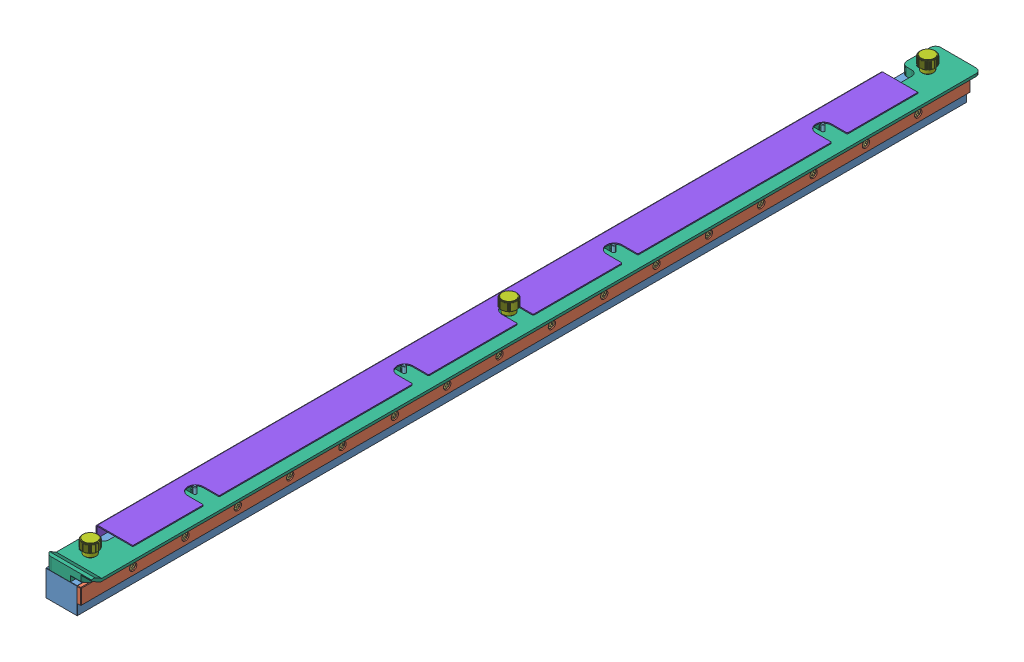
SolidWorks assembly Assemblage, configuration Défaut. Lengths in mm.
Overall size (95 92 1700).
40 component instances, 10 part files, 81 mates.
Components (placement in the parent):
- platine laterale-1: platine laterale [Défaut] at (-34.0319 -22.1151 2250) size (60 50 1700)
- teflon lateral-1: teflon lateral [Défaut] at (25.9681 -2.1151 2250) x (0 0 -1) z (1 0 0) size (1700 30 7)
- vis-1: vis [Défaut] at (31.6181 12.8849 2150) x (-1 0 0) z (0 -0.924225 -0.381849) size (12.65 11.3 11.3)
- vis-2: vis [Défaut] at (31.6181 12.8849 1950) x (-1 0 0) z (0 -0.924225 -0.381849) size (12.65 11.3 11.3)
- vis-3: vis [Défaut] at (31.6181 12.8849 2050) x (-1 0 0) z (0 -0.924225 -0.381849) size (12.65 11.3 11.3)
- vis-4: vis [Défaut] at (31.6181 12.8849 1850) x (-1 0 0) z (0 -0.924225 -0.381849) size (12.65 11.3 11.3)
- vis-5: vis [Défaut] at (31.6181 12.8849 1750) x (-1 0 0) z (0 -0.178078 0.984016) size (12.65 11.3 11.3)
- vis-6: vis [Défaut] at (31.6181 12.8849 1650) x (-1 0 0) z (0 0.474768 -0.880111) size (12.65 11.3 11.3)
- vis-8: vis [Défaut] at (31.6181 12.8849 1550) x (-1 0 0) z (0 -0.634119 -0.773236) size (12.65 11.3 11.3)
- vis-9: vis [Défaut] at (31.6181 12.8849 1450) x (-1 0 0) z (0 -0.237453 0.971399) size (12.65 11.3 11.3)
- vis-10: vis [Défaut] at (31.6181 12.8849 1350) x (-1 0 0) z (0 -0.971622 0.236541) size (12.65 11.3 11.3)
- vis-11: vis [Défaut] at (31.6181 12.8849 1250) x (-1 0 0) z (0 -0.306125 -0.951991) size (12.65 11.3 11.3)
- vis-12: vis [Défaut] at (31.6181 12.8849 1150) x (-1 0 0) z (0 -0.680899 0.732377) size (12.65 11.3 11.3)
- vis-13: vis [Défaut] at (31.6181 12.8849 1050) x (-1 0 0) z (0 -0.480013 0.877262) size (12.65 11.3 11.3)
- vis-14: vis [Défaut] at (31.6181 12.8849 950) x (-1 0 0) z (0 -0.325442 -0.945562) size (12.65 11.3 11.3)
- vis-15: vis [Défaut] at (31.6181 12.8849 850) x (-1 0 0) z (0 -0.999367 -0.035574) size (12.65 11.3 11.3)
- vis-16: vis [Défaut] at (31.6181 12.8849 750) x (-1 0 0) z (0 -0.091177 0.995835) size (12.65 11.3 11.3)
- vis-17: vis [Défaut] at (31.6181 12.8849 650) x (-1 0 0) z (0 -0.904322 0.426851) size (12.65 11.3 11.3)
- tige filetee-6: tige filetee [Défaut] at (0.9681 6.8849 2200) x (-0.474745 0 0.880123) z (0 1 0) size (8.23 8 60.82)
- tige filetee-7: tige filetee [Défaut] at (0.9681 6.8849 600) x (-0.873701 0 0.486463) z (0 1 0) size (8.23 8 60.82)
- pige-1: pige [Défaut] at (0.9681 5.8849 2000) x (-0.994545 0 0.104312) z (0 1 0) size (6 6 50)
- pige-2: pige [Défaut] at (0.9681 5.8849 1200) x (0.060452 0 -0.998171) z (0 1 0) size (6 6 50)
- pige-3: pige [Défaut] at (0.9681 5.8849 800) x (0.10136 0 0.99485) z (0 1 0) size (6 6 50)
- pige-4: pige [Défaut] at (0.9681 5.8849 1600) x (-0.928161 0 -0.37218) z (0 1 0) size (6 6 50)
- ski-1: ski [Défaut] at (-34.0319 27.8849 2250) size (87 23.5 1700)
- bouton molete-1: bouton molete [Défaut] at (0.9681 43.8849 600) x (0.383728 0 0.923446) z (-0.923446 0 0.383728) size (30 26 29.98)
- bouton molete-2: bouton molete [Défaut] at (0.9681 43.8849 2200) x (0.858497 0 0.512818) z (-0.512818 0 0.858497) size (30 26 29.98)
- equerre-1: equerre [Défaut] at (-37.6319 -17.1151 650) x (0 0 1) z (-1 0 0) size (1500 65 70)
- rondelle plate-1: rondelle plate [Défaut] at (-34.0319 2.8849 670) x (0 0 1) z (-1 0 0) size (16 16 1.6)
- rondelle plate-2: rondelle plate [Défaut] at (-34.0319 2.8849 1035) x (0 0 1) z (-1 0 0) size (16 16 1.6)
- rondelle plate-3: rondelle plate [Défaut] at (-34.0319 2.8849 2130) x (0 0 1) z (-1 0 0) size (16 16 1.6)
- rondelle plate-4: rondelle plate [Défaut] at (-34.0319 2.8849 1765) x (0 0 1) z (-1 0 0) size (16 16 1.6)
- rondelle plate-5: rondelle plate [Défaut] at (-34.0319 2.8849 1400) x (0 0 1) z (-1 0 0) size (16 16 1.6)
- vis bombe m8-6: vis bombe m8 [Défaut] at (-42.0319 2.8849 670) size (19.4 17.8 17.8)
- vis bombe m8-7: vis bombe m8 [Défaut] at (-42.0319 2.8849 1035) size (19.4 17.8 17.8)
- vis bombe m8-8: vis bombe m8 [Défaut] at (-42.0319 2.8849 1400) size (19.4 17.8 17.8)
- vis bombe m8-9: vis bombe m8 [Défaut] at (-42.0319 2.8849 1765) size (19.4 17.8 17.8)
- vis bombe m8-10: vis bombe m8 [Défaut] at (-42.0319 2.8849 2130) size (19.4 17.8 17.8)
- tige filetee-8: tige filetee [Défaut] at (0.9681 6.8849 1400) x (0.48993 0 -0.871762) z (0 1 0) size (8.23 8 60.82)
- bouton molete-3: bouton molete [Défaut] at (0.9681 43.8849 1400) x (0.825158 0 0.564902) z (-0.564902 0 0.825158) size (30 26 29.98)
Mates (geometry in assembly coordinates):
- Coaxiale1: concentric aligned: cylinder of teflon lateral-1 through (32.9681 12.8849 2150) axis (-1 0 0) radius 3; cylinder of vis-1 through (18.9681 12.8849 2150) axis (-1 0 0) radius 3
- Coaxiale2: concentric aligned: cylinder of teflon lateral-1 through (32.9681 12.8849 2050) axis (-1 0 0) radius 3; cylinder of vis-3 through (18.9681 12.8849 2050) axis (-1 0 0) radius 3
- Coïncidente1: coincident anti-aligned: plane of platine laterale-1 through (25.9681 -22.1151 550) normal (1 0 0); plane of teflon lateral-1 through (25.9681 -2.1151 2250) normal (-1 0 0)
- Coaxiale3: concentric aligned: cylinder of vis-1 through (18.9681 12.8849 2150) axis (-1 0 0) radius 3; cone of platine laterale-1 through (25.9681 12.8849 2150) axis (-1 0 0)
- Coïncidente2: coincident aligned: cone of teflon lateral-1 through (28.9681 12.8849 2150) axis (-1 0 0); cone of vis-1 through (28.9681 12.8849 2150) axis (-1 0 0)
- Coaxiale4: concentric aligned: cylinder of teflon lateral-1 through (32.9681 12.8849 2050) axis (-1 0 0) radius 3; cylinder of vis-3 through (18.9681 12.8849 2050) axis (-1 0 0) radius 3
- Coaxiale5: concentric aligned: cone of platine laterale-1 through (25.9681 12.8849 1950) axis (-1 0 0); cylinder of vis-2 through (18.9681 12.8849 1950) axis (-1 0 0) radius 3
- Coaxiale6: concentric aligned: cylinder of vis-4 through (18.9681 12.8849 1850) axis (-1 0 0) radius 3; cone of platine laterale-1 through (25.9681 12.8849 1850) axis (-1 0 0)
- Coïncidente3: coincident aligned: cone of teflon lateral-1 through (28.9681 12.8849 2050) axis (-1 0 0); cone of vis-3 through (28.9681 12.8849 2050) axis (-1 0 0)
- Coïncidente4: coincident aligned: cone of teflon lateral-1 through (28.9681 12.8849 1950) axis (-1 0 0); cone of vis-2 through (28.9681 12.8849 1950) axis (-1 0 0)
- Coïncidente5: coincident aligned: cone of teflon lateral-1 through (28.9681 12.8849 1850) axis (-1 0 0); cone of vis-4 through (28.9681 12.8849 1850) axis (-1 0 0)
- Coaxiale21: concentric aligned: cylinder of vis-5 through (18.9681 12.8849 1750) axis (-1 0 0) radius 3; cone of platine laterale-1 through (25.9681 12.8849 1750) axis (-1 0 0)
- Coïncidente26: coincident aligned: cone of teflon lateral-1 through (28.9681 12.8849 1750) axis (-1 0 0); cone of vis-5 through (28.9681 12.8849 1750) axis (-1 0 0)
- Coaxiale22: concentric anti-aligned: cylinder of platine laterale-1 through (25.9681 12.8849 1650) axis (1 0 0) radius 2.5; cylinder of vis-6 through (18.9681 12.8849 1650) axis (-1 0 0) radius 3
- Coïncidente27: coincident aligned: cone of teflon lateral-1 through (28.9681 12.8849 1650) axis (-1 0 0); cone of vis-6 through (28.9681 12.8849 1650) axis (-1 0 0)
- Coaxiale23: concentric anti-aligned: cylinder of platine laterale-1 through (25.9681 12.8849 1550) axis (1 0 0) radius 2.5; cylinder of vis-8 through (18.9681 12.8849 1550) axis (-1 0 0) radius 3
- Coïncidente28: coincident aligned: cone of teflon lateral-1 through (28.9681 12.8849 1550) axis (-1 0 0); cone of vis-8 through (28.9681 12.8849 1550) axis (-1 0 0)
- Coaxiale24: concentric anti-aligned: cylinder of platine laterale-1 through (25.9681 12.8849 1450) axis (1 0 0) radius 2.5; cylinder of vis-9 through (18.9681 12.8849 1450) axis (-1 0 0) radius 3
- Coïncidente29: coincident aligned: cone of teflon lateral-1 through (28.9681 12.8849 1450) axis (-1 0 0); cone of vis-9 through (28.9681 12.8849 1450) axis (-1 0 0)
- Coaxiale25: concentric anti-aligned: cylinder of platine laterale-1 through (25.9681 12.8849 1350) axis (1 0 0) radius 2.5; cylinder of vis-10 through (18.9681 12.8849 1350) axis (-1 0 0) radius 3
- Coïncidente30: coincident aligned: cone of teflon lateral-1 through (28.9681 12.8849 1350) axis (-1 0 0); cone of vis-10 through (28.9681 12.8849 1350) axis (-1 0 0)
- Coaxiale26: concentric anti-aligned: cylinder of platine laterale-1 through (25.9681 12.8849 1250) axis (1 0 0) radius 2.5; cylinder of vis-11 through (18.9681 12.8849 1250) axis (-1 0 0) radius 3
- Coïncidente31: coincident aligned: cone of teflon lateral-1 through (28.9681 12.8849 1250) axis (-1 0 0); cone of vis-11 through (28.9681 12.8849 1250) axis (-1 0 0)
- Coaxiale27: concentric anti-aligned: cylinder of platine laterale-1 through (25.9681 12.8849 1150) axis (1 0 0) radius 2.5; cylinder of vis-12 through (18.9681 12.8849 1150) axis (-1 0 0) radius 3
- Coïncidente32: coincident aligned: cone of teflon lateral-1 through (28.9681 12.8849 1150) axis (-1 0 0); cone of vis-12 through (28.9681 12.8849 1150) axis (-1 0 0)
- Coaxiale28: concentric anti-aligned: cylinder of platine laterale-1 through (25.9681 12.8849 1050) axis (1 0 0) radius 2.5; cylinder of vis-13 through (18.9681 12.8849 1050) axis (-1 0 0) radius 3
- Coïncidente33: coincident aligned: cone of teflon lateral-1 through (28.9681 12.8849 1050) axis (-1 0 0); cone of vis-13 through (28.9681 12.8849 1050) axis (-1 0 0)
- Coaxiale29: concentric anti-aligned: cylinder of platine laterale-1 through (25.9681 12.8849 950) axis (1 0 0) radius 2.5; cylinder of vis-14 through (18.9681 12.8849 950) axis (-1 0 0) radius 3
- Coïncidente34: coincident aligned: cone of teflon lateral-1 through (28.9681 12.8849 950) axis (-1 0 0); cone of vis-14 through (28.9681 12.8849 950) axis (-1 0 0)
- Coaxiale30: concentric anti-aligned: cylinder of platine laterale-1 through (25.9681 12.8849 850) axis (1 0 0) radius 2.5; cylinder of vis-15 through (18.9681 12.8849 850) axis (-1 0 0) radius 3
- Coïncidente35: coincident aligned: cone of teflon lateral-1 through (28.9681 12.8849 850) axis (-1 0 0); cone of vis-15 through (28.9681 12.8849 850) axis (-1 0 0)
- Coaxiale31: concentric anti-aligned: cylinder of platine laterale-1 through (25.9681 12.8849 750) axis (1 0 0) radius 2.5; cylinder of vis-16 through (18.9681 12.8849 750) axis (-1 0 0) radius 3
- Coïncidente36: coincident aligned: cone of teflon lateral-1 through (28.9681 12.8849 750) axis (-1 0 0); cone of vis-16 through (28.9681 12.8849 750) axis (-1 0 0)
- Coaxiale32: concentric anti-aligned: cylinder of platine laterale-1 through (25.9681 12.8849 650) axis (1 0 0) radius 2.5; cylinder of vis-17 through (18.9681 12.8849 650) axis (-1 0 0) radius 3
- Coïncidente37: coincident aligned: cone of teflon lateral-1 through (28.9681 12.8849 650) axis (-1 0 0); cone of vis-17 through (28.9681 12.8849 650) axis (-1 0 0)
- Coaxiale33: concentric anti-aligned: cylinder of platine laterale-1 through (0.9681 27.8849 2200) axis (0 1 0) radius 3.5; cylinder of tige filetee-6 through (0.9681 66.8849 2200) axis (0 -1 0) radius 4
- Coïncidente38: coincident anti-aligned: circle of platine laterale-1; plane of tige filetee-6 through (0.9681 6.8849 2200) normal (0 -1 0)
- Coaxiale39: concentric anti-aligned: cylinder of tige filetee-6 through (0.9681 66.8849 2200) axis (0 -1 0) radius 4; cylinder of bouton molete-2 through (0.9681 68.8849 2200) axis (0 1 0) radius 4
- Coaxiale47: concentric anti-aligned: cylinder of platine laterale-1 through (0.9681 27.8849 2000) axis (0 1 0) radius 3; cylinder of pige-1 through (0.9681 55.8849 2000) axis (0 -1 0) radius 3
- Coaxiale48: concentric anti-aligned: cylinder of platine laterale-1 through (0.9681 27.8849 1600) axis (0 1 0) radius 3; cylinder of pige-4 through (0.9681 55.8849 1600) axis (0 -1 0) radius 3
- Coïncidente57: coincident aligned: circle of platine laterale-1; circle of pige-4
- Coïncidente58: coincident aligned: circle of platine laterale-1; circle of pige-1
- Coaxiale49: concentric anti-aligned: cylinder of platine laterale-1 through (0.9681 27.8849 1200) axis (0 1 0) radius 3; cylinder of pige-2 through (0.9681 55.8849 1200) axis (0 -1 0) radius 3
- Coïncidente59: coincident aligned: circle of platine laterale-1; circle of pige-2
- Coaxiale50: concentric anti-aligned: cylinder of platine laterale-1 through (0.9681 27.8849 800) axis (0 1 0) radius 3; cylinder of pige-3 through (0.9681 55.8849 800) axis (0 -1 0) radius 3
- Coïncidente60: coincident aligned: circle of platine laterale-1; circle of pige-3
- Coïncidente61: coincident anti-aligned: plane of platine laterale-1 through (-34.0319 27.8849 550) normal (0 1 0); plane of ski-1 through (-34.0319 27.8849 550) normal (0 -1 0)
- DistanceLimite8: limit distance = 0 mm aligned: plane of ski-1 through (-34.0319 27.8849 550) normal (-1 0 0); plane of platine laterale-1 through (-34.0319 -22.1151 550) normal (-1 0 0)
- Coaxiale52: concentric anti-aligned: cylinder of tige filetee-7 through (0.9681 66.8849 600) axis (0 -1 0) radius 4; cylinder of bouton molete-1 through (0.9681 68.8849 600) axis (0 1 0) radius 4
- Coïncidente66: coincident anti-aligned: plane of rondelle plate-1 through (-35.6319 2.8849 670) normal (-1 0 0); plane of equerre-1 through (-35.6319 -17.1151 650) normal (1 0 0)
- Coaxiale55: concentric aligned: cylinder of platine laterale-1 through (-34.0319 2.8849 670) axis (-1 0 0) radius 3.4; cylinder of equerre-1 through (32.3691 2.8849 670) axis (-1 0 0) radius 4.5
- Coaxiale56: concentric aligned: cylinder of platine laterale-1 through (-34.0319 2.8849 1035) axis (-1 0 0) radius 3.4; cylinder of equerre-1 through (32.3691 2.8849 1035) axis (-1 0 0) radius 4.5
- DistanceLimite12: limit distance = 0 mm aligned: plane of ski-1 through (-34.0319 27.8849 2250) normal (0 0 1); plane of platine laterale-1 through (-34.0319 -22.1151 2250) normal (0 0 1)
- Coaxiale64: concentric anti-aligned: cylinder of platine laterale-1 through (-34.0319 2.8849 670) axis (-1 0 0) radius 3.4; cylinder of rondelle plate-1 through (-35.6319 2.8849 670) axis (1 0 0) radius 4.2
- Coïncidente77: coincident anti-aligned: plane of platine laterale-1 through (-34.0319 -22.1151 550) normal (-1 0 0); plane of rondelle plate-1 through (-34.0319 2.8849 670) normal (1 0 0)
- Coaxiale65: concentric anti-aligned: cylinder of platine laterale-1 through (-34.0319 2.8849 1035) axis (-1 0 0) radius 3.4; cylinder of rondelle plate-2 through (-35.6319 2.8849 1035) axis (1 0 0) radius 4.2
- Coïncidente78: coincident anti-aligned: plane of platine laterale-1 through (-34.0319 -22.1151 550) normal (-1 0 0); plane of rondelle plate-2 through (-34.0319 2.8849 1035) normal (1 0 0)
- Coaxiale66: concentric anti-aligned: cylinder of platine laterale-1 through (-34.0319 2.8849 1400) axis (-1 0 0) radius 3.4; cylinder of rondelle plate-5 through (-35.6319 2.8849 1400) axis (1 0 0) radius 4.2
- Coïncidente79: coincident anti-aligned: plane of platine laterale-1 through (-34.0319 -22.1151 550) normal (-1 0 0); plane of rondelle plate-5 through (-34.0319 2.8849 1400) normal (1 0 0)
- Coaxiale67: concentric anti-aligned: cylinder of platine laterale-1 through (-34.0319 2.8849 1765) axis (-1 0 0) radius 3.4; cylinder of rondelle plate-4 through (-35.6319 2.8849 1765) axis (1 0 0) radius 4.2
- Coïncidente80: coincident anti-aligned: plane of platine laterale-1 through (-34.0319 -22.1151 550) normal (-1 0 0); plane of rondelle plate-4 through (-34.0319 2.8849 1765) normal (1 0 0)
- Coaxiale68: concentric anti-aligned: cylinder of platine laterale-1 through (-34.0319 2.8849 2130) axis (-1 0 0) radius 3.4; cylinder of rondelle plate-3 through (-35.6319 2.8849 2130) axis (1 0 0) radius 4.2
- Coïncidente81: coincident anti-aligned: plane of platine laterale-1 through (-34.0319 -22.1151 550) normal (-1 0 0); plane of rondelle plate-3 through (-34.0319 2.8849 2130) normal (1 0 0)
- Coaxiale69: concentric aligned: cylinder of vis bombe m8-6 through (-22.6319 2.8849 670) axis (-1 0 0) radius 4; cylinder of platine laterale-1 through (-34.0319 2.8849 670) axis (-1 0 0) radius 3.4
- Coïncidente82: coincident anti-aligned: plane of equerre-1 through (-37.6319 -17.1151 650) normal (-1 0 0); plane of vis bombe m8-6 through (-37.6319 11.3449 670) normal (1 0 0)
- Coaxiale70: concentric aligned: cylinder of platine laterale-1 through (-34.0319 2.8849 1035) axis (-1 0 0) radius 3.4; cylinder of vis bombe m8-7 through (-22.6319 2.8849 1035) axis (-1 0 0) radius 4
- Coïncidente83: coincident anti-aligned: plane of equerre-1 through (-37.6319 -17.1151 650) normal (-1 0 0); plane of vis bombe m8-7 through (-37.6319 11.3449 1035) normal (1 0 0)
- Coaxiale71: concentric aligned: cylinder of platine laterale-1 through (-34.0319 2.8849 1400) axis (-1 0 0) radius 3.4; cylinder of vis bombe m8-8 through (-22.6319 2.8849 1400) axis (-1 0 0) radius 4
- Coïncidente84: coincident anti-aligned: plane of equerre-1 through (-37.6319 -17.1151 650) normal (-1 0 0); plane of vis bombe m8-8 through (-37.6319 11.3449 1400) normal (1 0 0)
- Coaxiale72: concentric aligned: cylinder of platine laterale-1 through (-34.0319 2.8849 1765) axis (-1 0 0) radius 3.4; cylinder of vis bombe m8-9 through (-22.6319 2.8849 1765) axis (-1 0 0) radius 4
- Coïncidente85: coincident anti-aligned: plane of equerre-1 through (-37.6319 -17.1151 650) normal (-1 0 0); plane of vis bombe m8-9 through (-37.6319 11.3449 1765) normal (1 0 0)
- Coaxiale73: concentric aligned: cylinder of platine laterale-1 through (-34.0319 2.8849 2130) axis (-1 0 0) radius 3.4; cylinder of vis bombe m8-10 through (-22.6319 2.8849 2130) axis (-1 0 0) radius 4
- Coïncidente86: coincident anti-aligned: plane of equerre-1 through (-37.6319 -17.1151 650) normal (-1 0 0); plane of vis bombe m8-10 through (-37.6319 11.3449 2130) normal (1 0 0)
- Coaxiale74: concentric anti-aligned: cylinder of platine laterale-1 through (0.9681 27.8849 1400) axis (0 1 0) radius 3.5; cylinder of tige filetee-8 through (0.9681 66.8849 1400) axis (0 -1 0) radius 4
- Coïncidente87: coincident anti-aligned: circle of platine laterale-1; plane of tige filetee-8 through (0.9681 6.8849 1400) normal (0 -1 0)
- Coaxiale75: concentric anti-aligned: cylinder of tige filetee-8 through (0.9681 66.8849 1400) axis (0 -1 0) radius 4; cylinder of bouton molete-3 through (0.9681 68.8849 1400) axis (0 1 0) radius 4
- Coaxiale76: concentric anti-aligned: cylinder of platine laterale-1 through (0.9681 27.8849 600) axis (0 1 0) radius 3.5; cylinder of tige filetee-7 through (0.9681 66.8849 600) axis (0 -1 0) radius 4
- Coïncidente88: coincident anti-aligned: circle of platine laterale-1; plane of tige filetee-7 through (0.9681 6.8849 600) normal (0 -1 0)
- DistanceLimite13: limit distance = 0 mm anti-aligned: plane of bouton molete-1 through (-0.5668 43.8849 596.3062) normal (0 -1 0); plane of ski-1 through (-34.0329 43.8849 2230) normal (0 1 0)
- DistanceLimite14: limit distance = 0 mm anti-aligned: plane of bouton molete-2 through (-2.4659 43.8849 2197.9487) normal (0 -1 0); plane of ski-1 through (-34.0329 43.8849 2230) normal (0 1 0)
- DistanceLimite15: limit distance = 0 mm anti-aligned: plane of ski-1 through (-34.0329 43.8849 2230) normal (0 1 0); plane of bouton molete-3 through (-2.3326 43.8849 1397.7404) normal (0 -1 0)
